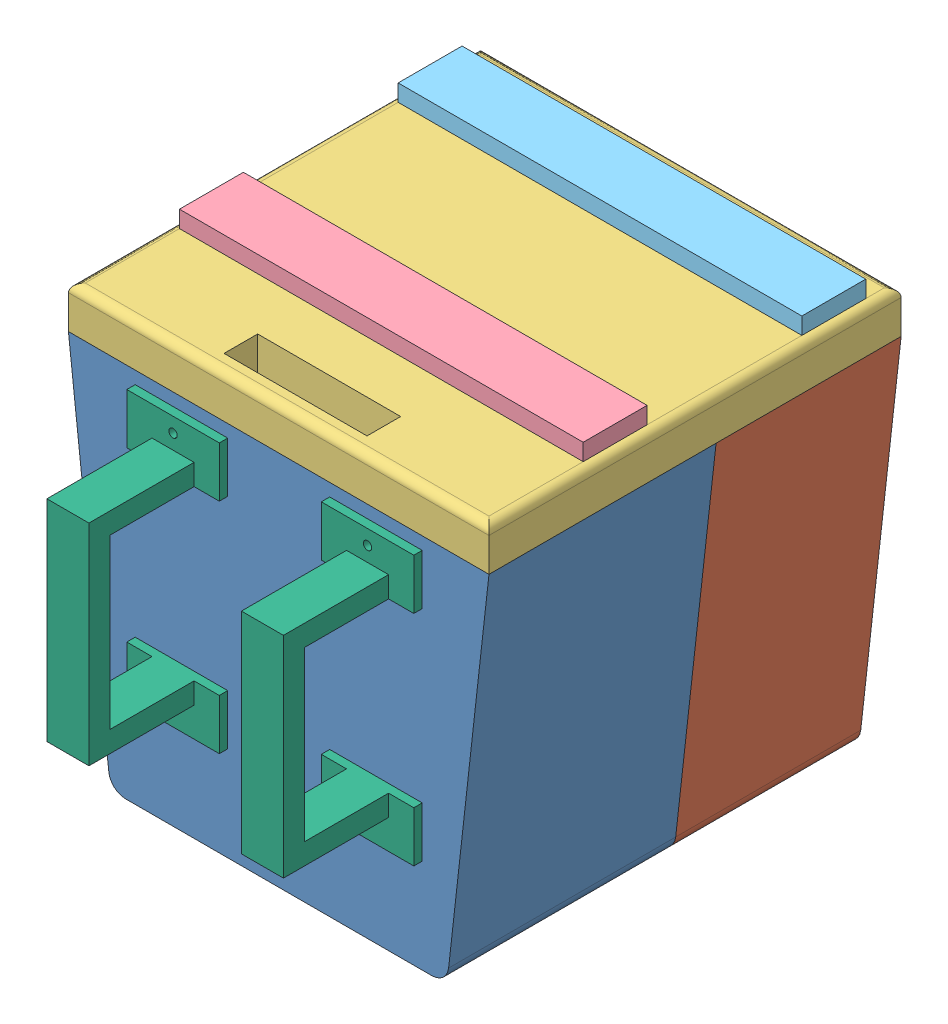
SolidWorks assembly Enclosure, configuration Default. Lengths in mm.
Overall size (127 131.37 158.75).
7 component instances, 6 part files, 19 mates.
Components (placement in the parent):
- Enclosure[BACK]-1: Enclosure[BACK] [Default] at origin size (127 113.59 68.58)
- Enclosure[FRONT]-1: Enclosure[FRONT] [Default] at (0 0 -124.46) x (-1 0 0) z (0 0 -1) size (127 113.59 55.88)
- Enclosure[TOP]-1: Enclosure[TOP] [Default] at (0 56.7961 -43.18) size (127 12.7 124.46)
- EnclosurePMBoard-1: EnclosurePMBoard [Default] at (-4.9216 2.8677 -38.354) size (121.92 126.16 19.3)
- EnclosureSensorBoard-1: EnclosureSensorBoard [Default] at (-4.9216 2.8677 -104.394) size (121.92 126.16 19.3)
- Arm Connection-1: Arm Connection [Default] at (23.0194 0 2.54) size (27.94 81.28 34.29)
- Arm Connection-2: Arm Connection [Default] at (-35.7194 0 2.54) size (27.94 81.28 34.29)
Mates (geometry in assembly coordinates):
- Parallel1: parallel anti-aligned: line of Enclosure[FRONT]-1 through (-63.5 56.7961 -68.58) axis (0 0 -1); line of Enclosure[TOP]-1 through (-63.5 56.7961 -124.46) axis (0 0 1)
- Coincident12: coincident anti-aligned: plane of Enclosure[BACK]-1 through (63.5 56.7961 -5.08) normal (0 1 0); plane of Enclosure[TOP]-1 through (0 56.7961 -43.18) normal (0 -1 0)
- Coincident13: coincident anti-aligned: line of Enclosure[FRONT]-1 through (-63.5 56.7961 -124.46) axis (1 0 0); line of Enclosure[TOP]-1 through (63.5 56.7961 -124.46) axis (-1 0 0)
- Coincident14: coincident anti-aligned: line of Enclosure[BACK]-1 through (63.5 56.7961 -68.58) axis (0 0 1); line of Enclosure[TOP]-1 through (63.5 56.7961 0) axis (0 0 -1)
- Distance3: distance = 0.254 mm: plane of EnclosurePMBoard-1 through (-41.5856 -46.5056 -38.354) normal (0 0 1); line of Enclosure[TOP]-1 through (-57.6928 69.4961 -38.1) axis (1 0 0)
- Coincident42: coincident anti-aligned: plane of Enclosure[TOP]-1 through (0 69.4961 -43.18) normal (0 1 0); plane of EnclosurePMBoard-1 through (-4.9216 69.4961 -38.354) normal (0 -1 0)
- Coincident43: coincident aligned: line of Enclosure[TOP]-1 through (-60.96 69.4961 -121.92) axis (0 0 1); line of EnclosurePMBoard-1 through (-60.96 69.4961 -50.292) axis (0 0 1)
- Coincident44: coincident aligned: line of Enclosure[TOP]-1 through (60.96 69.4961 -2.54) axis (0 0 -1); line of EnclosurePMBoard-1 through (60.96 69.4961 -30.988) axis (0 0 -1)
- Distance5: distance = 0.254 mm: plane of EnclosureBoards-7 through (-41.5856 -46.5056 -108.966) normal (0 0 -1); line of Enclosure[TOP]-1 through (57.6928 69.4961 -109.22) axis (-1 0 0)
- Coincident47: coincident aligned: line of Enclosure[TOP]-1 through (-60.96 69.4961 -121.92) axis (0 0 1); line of EnclosureSensorBoard-1 through (-60.96 69.4961 -116.332) axis (0 0 1)
- Parallel14: parallel aligned: line of EnclosureSensorBoard-1 through (60.96 69.4961 -116.332) axis (-1 0 0); line of Enclosure[TOP]-1 through (60.96 69.4961 -121.92) axis (-1 0 0)
- Coincident49: coincident anti-aligned: plane of Enclosure[BACK]-1 through (0 0 -68.58) normal (0 0 -1); plane of Enclosure[FRONT]-1 through (0 0 -68.58) normal (0 0 1)
- Coincident52: coincident aligned: plane of Enclosure[BACK]-1 through (63.5 56.7961 -5.08) normal (0.993808 -0.111111 0); plane of Enclosure[FRONT]-1 through (56.4444 -6.3107 -119.38) normal (0.993808 -0.111111 0)
- Coincident53: coincident anti-aligned: plane of Enclosure[BACK]-1 through (46.2563 -51.7161 0) normal (0 0 1); plane of Arm Connection-1 through (23.0194 0 0) normal (0 0 -1)
- Distance7: distance = 3.81 mm: line of Enclosure[TOP]-1 through (-63.5 56.7961 0) axis (1 0 0); line of Arm Connection-1 through (27.94 15.3994 52.9861) axis (0 1 0)
- Distance8: distance = 20.32 mm: line of Arm Connection-1 through (43.3394 52.9861 2.54) axis (0 -1 0); line of Enclosure[TOP]-1 through (10.16 63.5 66.9561) axis (0 0 -1)
- Coincident67: coincident anti-aligned: plane of Enclosure[BACK]-1 through (46.2563 -51.7161 0) normal (0 0 1); plane of Arm Connection-2 through (-35.7194 0 0) normal (0 0 -1)
- Distance15: distance = 3.81 mm: line of Enclosure[TOP]-1 through (-63.5 56.7961 0) axis (1 0 0); line of Arm Connection-2 through (27.94 -43.3394 52.9861) axis (0 1 0)
- Distance16: distance = 20.32 mm: line of Arm Connection-2 through (-43.3394 37.7461 2.54) axis (0 1 0); point of Enclosure[BACK]-1
